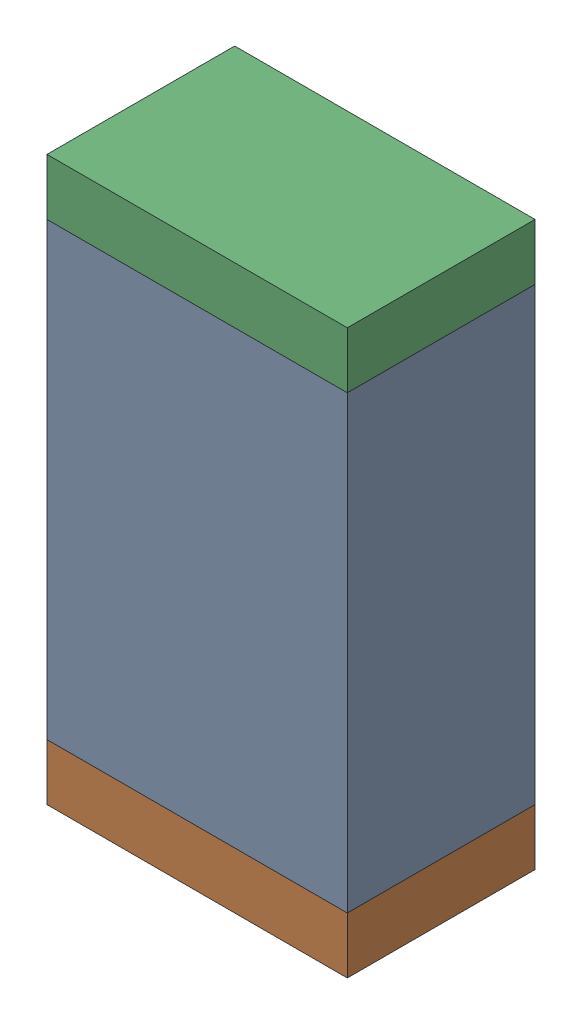
SolidWorks assembly R50, configuration Default. Lengths in mm.
Overall size (0.8 1.5 0.5).
6 component instances, 2 part files, 0 mates.
Components (placement in the parent):
- 810156976-1: 810156976 [Default] at (114 60.45 0) size (0.8 1.2 0.5)
  - Extruded_6-1: Extruded_6 [Default] at origin size (0.8 1.2 0.5)
- 810156592-1: 810156592 [Default] at (114 59.775 0) size (0.8 0.15 0.5)
  - Extruded_7-1: Extruded_7 [Default] at origin size (0.8 0.15 0.5)
- 810156592-2: 810156592 [Default] at (114 61.125 0) size (0.8 0.15 0.5)
  - Extruded_7-1: Extruded_7 [Default] at origin size (0.8 0.15 0.5)
